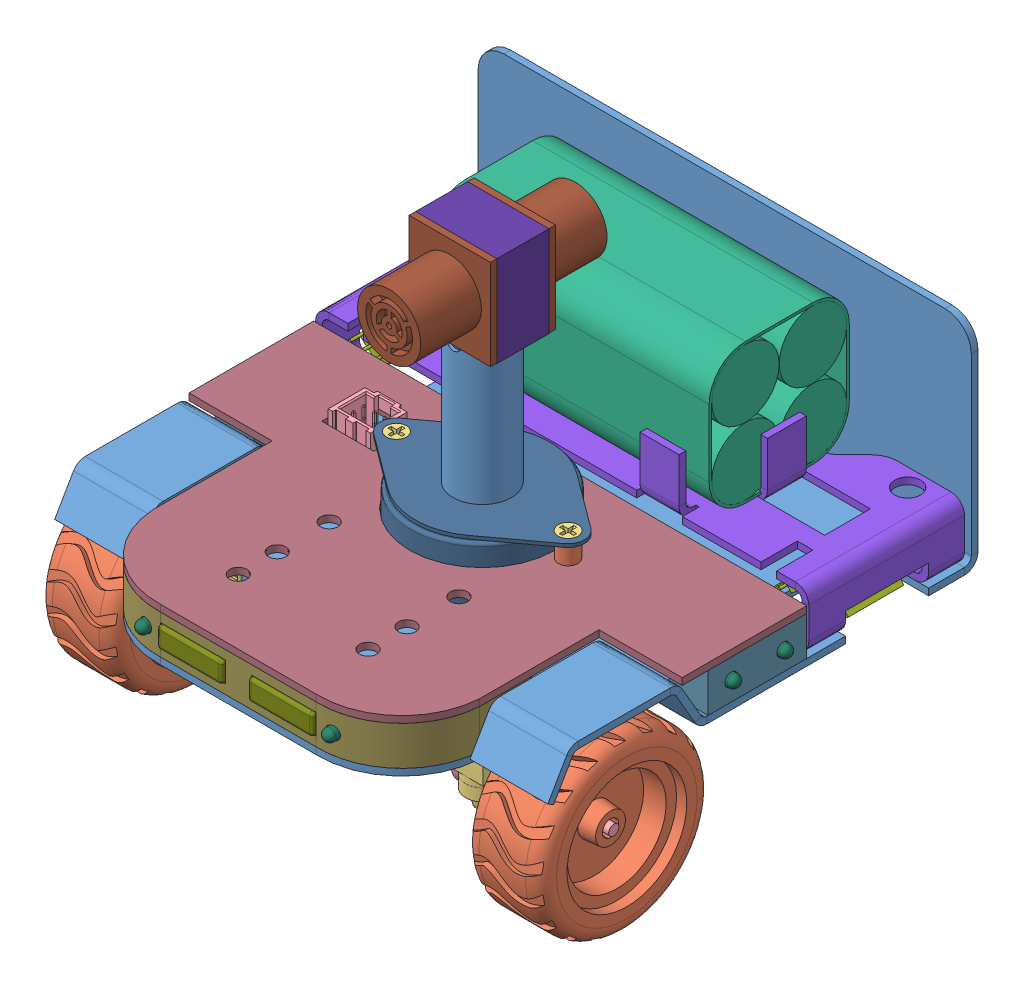
SolidWorks assembly REAR, TOP LEVEL, configuration Default. Lengths in mm.
Overall size (124.43 108.12 122.55).
41 component instances, 22 part files, 83 mates.
Components (placement in the parent):
- PLATE, REAR-1: PLATE, REAR [Default] at (-42.1312 28.0774 12.7174) size (120.65 52.45 120.66)
- WHEEL ASSEMBLY-1: WHEEL ASSEMBLY [Default-_flexible1] at (7.6153 26.9792 58.7651) x (0 0 1) z (1 0 0) size (42.46 78.6 70.03) (flexible)
  - Pololu 49x19 Wheel-1: Pololu 49x19 Wheel [Default] at (-19.8703 11.8393 2.4418) size (42.46 42.56 19)
  - Pololu Extended Micro Metal Bracket-1: Pololu Extended Micro Metal Bracket [Default] at (-19.8703 6.8393 -18.4366) size (26.6 22.49 26.04)
  - Pololu 298-1 Motor-1: Pololu 298-1 Motor [Default] at (-19.8703 11.8393 -25.1366) x (0 0 -1) z (0 1 0) size (35.87 12 10)
- WHEEL ASSEMBLY-2: WHEEL ASSEMBLY [Default-_flexible2] at (-91.8778 26.9792 19.0244) x (0 0 -1) z (-1 0 0) size (42.46 78.6 70.03) (flexible)
  - Pololu 49x19 Wheel-1: Pololu 49x19 Wheel [Default] at (-19.8703 11.8393 2.4418) size (42.46 42.56 19)
  - Pololu Extended Micro Metal Bracket-1: Pololu Extended Micro Metal Bracket [Default] at (-19.8703 6.8393 -18.4366) size (26.6 22.49 26.04)
  - Pololu 298-1 Motor-1: Pololu 298-1 Motor [Default] at (-19.8703 11.8393 -25.1366) x (0 0 -1) z (0 1 0) size (35.87 12 10)
- Socket Head Cap Screw_AI-1: Socket Head Cap Screw_AI [HX-SHCS 0.086-56x0.4375x0.4375-N] at (-77.6912 31.9128 47.8948) x (0 -1 0) z (-0.381305 0 -0.924449) size (13.3 3.56 3.56)
- Socket Head Cap Screw_AI-2: Socket Head Cap Screw_AI [HX-SHCS 0.086-56x0.4375x0.4375-N] at (-77.6912 31.9128 29.8948) x (0 -1 0) z (0 0 1) size (13.3 3.56 3.56)
- Socket Head Cap Screw_AI-3: Socket Head Cap Screw_AI [HX-SHCS 0.086-56x0.4375x0.4375-N] at (-6.5712 31.9128 29.8948) x (0 -1 0) z (0 0 1) size (13.3 3.56 3.56)
- Socket Head Cap Screw_AI-4: Socket Head Cap Screw_AI [HX-SHCS 0.086-56x0.4375x0.4375-N] at (-6.5712 31.9128 47.8948) x (0 -1 0) z (0 0 1) size (13.3 3.56 3.56)
- 4000mAh 7.4V Battery Pack-1: 4000mAh 7.4V Battery Pack [Default] at (-42.1312 61.2244 -25.7652) x (0 0 -1) z (1 0 0) size (34.29 34.29 68.58)
- SENSOR, GP2Y0D810-1: SENSOR, GP2Y0D810 [Default] at (9.9271 36.6454 -23.9555) x (0 0 -1) z (0.766044 0.642788 0) size (28.32 10.54 8.89)
- SENSOR, GP2Y0D810-2: SENSOR, GP2Y0D810 [Default] at (-94.1896 36.6454 -23.9555) x (0 0 -1) z (0.766044 -0.642788 0) size (28.32 10.54 8.89)
- Battery Support-1: Battery Support [Default] at (-42.1312 29.7284 -26.0192) size (120.65 27.05 38.1)
- Mounting Block-1: Mounting Block [Default] at (-42.1312 36.0784 -35.6712) x (-1 0 0) z (0 0 -1) size (22.23 12.7 25.4)
- PF35T-48-1: PF35T-48 [Default] at (-42.1312 31.7284 12.5888) size (50 29.2 35)
- MaxSonar EZ1-1: MaxSonar EZ1 [Default] at (-42.1452 90.9244 18.9388) x (0.999998 0 0.0022) z (-0.0022 0 0.999998) size (19.94 22.1 16.38)
- MaxSonar EZ1-2: MaxSonar EZ1 [Default] at (-42.1173 90.9244 6.2388) x (-0.999998 0 -0.0022) z (0.0022 0 -0.999998) size (19.94 22.1 16.38)
- BUMPER, REAR-1: BUMPER, REAR [Default] at (-42.1312 29.7284 53.2288) x (-1 0 0) z (0 0 -1) size (80.01 9.53 31.76)
- PLATE, REAR COVER-1: PLATE, REAR COVER [Default] at (-42.1312 39.2534 72.2788) size (120.65 1.65 78.75)
- MOUNTING BLOCK, COLOR SENSOR-1: MOUNTING BLOCK, COLOR SENSOR [Default] at (-97.6937 29.7284 5.6038) size (9.53 9.53 24.13)
- MOUNTING BLOCK, COLOR SENSOR-2: MOUNTING BLOCK, COLOR SENSOR [Default] at (13.4313 29.7284 5.6038) size (9.53 9.53 24.13)
- SENSOR, COLOR LED-1: SENSOR, COLOR LED [Default] at (-27.6486 42.7147 33.8533) x (0 0 -1) z (-0.713616 0.700538 0) size (5.83 3.66 3.66)
- SENSOR, COLOR LED-2: SENSOR, COLOR LED [Default] at (-64.9673 22.7516 33.8533) x (0 0 -1) z (0.002041 -0.999998 0) size (5.83 3.66 3.66)
- COPPER CONTACT-1: COPPER CONTACT [Default] at (-53.2437 34.4909 66.8178) size (15.88 5.08 6.35)
- COPPER CONTACT-2: COPPER CONTACT [Default] at (-31.0187 34.4909 66.8178) size (15.88 5.08 6.35)
- MOUNTING BLOCK, SONAR-1: MOUNTING BLOCK, SONAR [Default] at (-42.1173 90.8609 6.2388) x (0.999998 0 0.0022) z (-0.0022 0 0.999998) size (19.94 22.23 12.7)
- SHAFT, SONAR MOUNT-1: SHAFT, SONAR MOUNT [Default] at (-42.1312 52.5784 12.5888) x (-0.538443 0 0.842662) z (-0.842662 0 -0.538443) size (4.76 39.88 4.76)
- SHAFT, SONAR SUPPORT-1: SHAFT, SONAR SUPPORT [Default] at (-42.1312 46.7284 12.5888) size (14.22 33.25 14.22)
- SHAFT, STEPPER SUPPORT-1: SHAFT, STEPPER SUPPORT [Default] at (-63.1312 29.6724 12.5888) size (4.76 16.26 4.76)
- SHAFT, STEPPER SUPPORT-2: SHAFT, STEPPER SUPPORT [Default] at (-21.1312 29.6724 12.5888) x (0.987866 0 -0.155311) z (0.155311 0 0.987866) size (4.76 16.26 4.76)
- Flat Head 100 Screw_AI-2: Flat Head 100 Screw_AI [CR-FHM1 0.112-40x0.25x0.25-N] at (-63.1312 46.7284 12.5888) x (0 -1 0) z (0 0 1) size (6.35 4.85 4.85)
- Flat Head 100 Screw_AI-3: Flat Head 100 Screw_AI [CR-FHM1 0.112-40x0.25x0.25-N] at (-21.1312 46.7284 12.5888) x (0 -1 0) z (0 0 1) size (6.35 4.85 4.85)
- CONNECTOR, MOLEX 6 PIN-1: CONNECTOR, MOLEX 6 PIN [Default] at (-73.7219 38.6294 8.6439) size (10.34 13.8 9.75)
- SENSOR, COLOR LED-3: SENSOR, COLOR LED [Default] at (-64.0196 42.7147 3.5765) x (1 0 0) z (0 0.700538 -0.713616) size (5.83 3.66 3.66)
- SENSOR, COLOR LED-4: SENSOR, COLOR LED [Default] at (-64.0196 42.7147 -9.1235) x (1 0 0) z (0 0.700538 -0.713616) size (5.83 3.66 3.66)
- SENSOR, COLOR LED-5: SENSOR, COLOR LED [Default] at (-20.2429 42.7147 20.3311) x (-1 0 0) z (0 0.700538 0.713616) size (5.83 3.66 3.66)
- SENSOR, COLOR LED-6: SENSOR, COLOR LED [Default] at (-20.2429 42.7147 7.6311) x (-1 0 0) z (0 0.700538 0.713616) size (5.83 3.66 3.66)
Mates (geometry in assembly coordinates):
- Coincident1: coincident aligned: plane of WHEEL ASSEMBLY-1/Pololu Extended Micro Metal Bracket-1 through (6.4788 20.1399 25.5948) normal (0 1 0); plane of WHEEL ASSEMBLY-2/Pololu Extended Micro Metal Bracket-1 through (-90.7412 20.1399 52.1948) normal (0 1 0)
- Coincident2: coincident anti-aligned: plane of PLATE, REAR-1 through (-82.1362 28.0774 18.9388) normal (0 -1 0); plane of WHEEL ASSEMBLY-2/Pololu Extended Micro Metal Bracket-1 through (-66.7356 28.0774 52.1948) normal (0 1 0)
- Coincident3: coincident aligned: plane of Socket Head Cap Screw_AI-1 through (-77.6912 31.9128 47.8948) normal (0 1 0); plane of Socket Head Cap Screw_AI-2 through (-77.6912 31.9128 29.8948) normal (0 1 0)
- Coincident4: coincident aligned: plane of Socket Head Cap Screw_AI-3 through (-6.5712 31.9128 29.8948) normal (0 1 0); plane of Socket Head Cap Screw_AI-4 through (-6.5712 31.9128 47.8948) normal (0 1 0)
- Coincident5: coincident aligned: plane of Socket Head Cap Screw_AI-2 through (-77.6912 31.9128 29.8948) normal (0 1 0); plane of Socket Head Cap Screw_AI-3 through (-6.5712 31.9128 29.8948) normal (0 1 0)
- Coincident6: coincident anti-aligned: plane of PLATE, REAR-1 through (-82.1362 29.7284 18.9388) normal (0 1 0); plane of Socket Head Cap Screw_AI-3 through (-4.7932 29.7284 29.8948) normal (0 -1 0)
- Concentric6: concentric aligned: cylinder of PLATE, REAR-1; cylinder of Socket Head Cap Screw_AI-2
- Concentric7: concentric aligned: cylinder of PLATE, REAR-1; cylinder of Socket Head Cap Screw_AI-1
- Concentric8: concentric aligned: cylinder of PLATE, REAR-1; cylinder of Socket Head Cap Screw_AI-3
- Concentric9: concentric aligned: cylinder of PLATE, REAR-1; cylinder of Socket Head Cap Screw_AI-4
- Concentric40: concentric aligned: cylinder of WHEEL ASSEMBLY-2/Pololu Extended Micro Metal Bracket-1; cylinder of Socket Head Cap Screw_AI-2
- Concentric41: concentric aligned: cylinder of WHEEL ASSEMBLY-2/Pololu Extended Micro Metal Bracket-1; cylinder of Socket Head Cap Screw_AI-1
- Concentric42: concentric aligned: cylinder of WHEEL ASSEMBLY-1/Pololu Extended Micro Metal Bracket-1; cylinder of Socket Head Cap Screw_AI-3
- Concentric43: concentric aligned: cylinder of WHEEL ASSEMBLY-1/Pololu Extended Micro Metal Bracket-1; cylinder of Socket Head Cap Screw_AI-4
- Coincident91: coincident aligned: plane of PLATE, REAR-1 through (-42.1312 28.0774 12.7174) normal (1 0 0); plane of 4000mAh 7.4V Battery Pack-1 through (-42.1312 61.2244 -25.7652) normal (1 0 0)
- Coincident92: coincident anti-aligned: plane of PLATE, REAR-1 through (-85.9462 29.7284 -31.0357) normal (0.642788 0.766044 0); plane of SENSOR, GP2Y0D810-2 through (-97.5946 39.5026 -35.8427) normal (-0.642788 -0.766044 0)
- Concentric44: concentric aligned: cylinder of PLATE, REAR-1; cylinder of SENSOR, GP2Y0D810-2
- Parallel1: parallel anti-aligned: plane of PLATE, REAR-1 through (-97.7091 37.4434 -31.0357) normal (0 0 1); plane of SENSOR, GP2Y0D810-2 through (-89.7641 35.0043 -35.8427) normal (0 0 -1)
- Coincident93: coincident anti-aligned: plane of PLATE, REAR-1 through (1.6838 29.7284 -31.0357) normal (-0.642788 0.766044 0); plane of SENSOR, GP2Y0D810-1 through (6.522 33.7882 -35.8427) normal (0.642788 -0.766044 0)
- Concentric45: concentric aligned: cylinder of PLATE, REAR-1; cylinder of SENSOR, GP2Y0D810-1
- Parallel2: parallel aligned: plane of SENSOR, GP2Y0D810-1 through (12.3118 40.7187 -14.3797) normal (0.766044 0.642788 0); plane of PLATE, REAR-1 through (13.4467 37.4434 -35.7982) normal (0.766044 0.642788 0)
- Coincident97: coincident anti-aligned: plane of PLATE, REAR-1 through (-82.1362 29.7284 18.9388) normal (0 1 0); plane of Battery Support-1 through (18.1938 29.7284 -6.9692) normal (0 -1 0)
- Coincident98: coincident aligned: plane of PLATE, REAR-1 through (-42.1312 28.0774 12.7174) normal (1 0 0); plane of Battery Support-1 through (-42.1312 29.7284 -26.0192) normal (1 0 0)
- Coincident100: coincident aligned: plane of PLATE, REAR-1 through (-102.4562 28.0774 -36.3062) normal (0 0 1); plane of Battery Support-1 through (-89.7562 33.0304 -36.3062) normal (0 0 1)
- Coincident101: coincident anti-aligned: plane of 4000mAh 7.4V Battery Pack-1 through (-76.4212 69.4794 -8.6202) normal (0 0 1); plane of Battery Support-1 through (-23.0812 44.0794 -8.6202) normal (0 0 -1)
- Coincident102: coincident anti-aligned: plane of 4000mAh 7.4V Battery Pack-1 through (-76.4212 44.0794 -17.5102) normal (0 -1 0); plane of Battery Support-1 through (-102.4562 44.0794 -6.9692) normal (0 1 0)
- Coincident103: coincident anti-aligned: plane of PLATE, REAR-1 through (-82.1362 29.7284 18.9388) normal (0 1 0); plane of Mounting Block-1 through (-31.0187 29.7284 -48.3712) normal (0 -1 0)
- Concentric46: concentric aligned: cylinder of PLATE, REAR-1; cylinder of Mounting Block-1
- Concentric54: concentric aligned: cylinder of PLATE, REAR-1; cylinder of Mounting Block-1
- Coincident104: coincident anti-aligned: plane of PLATE, REAR-1 through (-82.1362 29.7284 18.9388) normal (0 1 0); plane of PF35T-48-1 through (-42.1312 29.7284 12.5888) normal (0 -1 0)
- Coincident105: coincident anti-aligned: plane of PLATE, REAR-1 through (-82.1362 29.7284 18.9388) normal (0 1 0); plane of BUMPER, REAR-1 through (-22.4072 29.7284 51.97) normal (0 -1 0)
- Coincident107: coincident aligned: plane of PLATE, REAR-1 through (-61.1812 28.0774 72.2788) normal (0 0 1); plane of BUMPER, REAR-1 through (-23.0812 39.2534 72.2788) normal (0 0 1)
- Concentric57: concentric anti-aligned: cylinder of PLATE, REAR-1; cylinder of BUMPER, REAR-1
- Coincident108: coincident anti-aligned: plane of BUMPER, REAR-1 through (-22.4072 39.2534 51.97) normal (0 1 0); plane of PLATE, REAR COVER-1 through (-61.8553 39.2534 51.97) normal (0 -1 0)
- Coincident109: coincident aligned: plane of PLATE, REAR-1 through (-61.1812 28.0774 72.2788) normal (0 0 1); plane of PLATE, REAR COVER-1 through (-23.0812 40.9044 72.2788) normal (0 0 1)
- Concentric58: concentric anti-aligned: cylinder of PLATE, REAR-1; cylinder of PLATE, REAR COVER-1
- Concentric59: concentric anti-aligned: cylinder of PF35T-48-1; cylinder of PLATE, REAR COVER-1
- Coincident110: coincident aligned: plane of MOUNTING BLOCK, COLOR SENSOR-1 through (-92.9312 39.2534 -6.4612) normal (0 1 0); plane of MOUNTING BLOCK, COLOR SENSOR-2 through (18.1938 39.2534 -6.4612) normal (0 1 0)
- Coincident111: coincident anti-aligned: plane of PLATE, REAR-1 through (-82.1362 29.7284 18.9388) normal (0 1 0); plane of MOUNTING BLOCK, COLOR SENSOR-1 through (-92.9312 29.7284 -6.4612) normal (0 -1 0)
- Coincident112: coincident aligned: plane of MOUNTING BLOCK, COLOR SENSOR-1 through (-102.4562 39.2534 -6.4612) normal (0 0 -1); plane of MOUNTING BLOCK, COLOR SENSOR-2 through (8.6688 39.2534 -6.4612) normal (0 0 -1)
- Coincident113: coincident: line of PLATE, REAR-1; plane of MOUNTING BLOCK, COLOR SENSOR-1 through (-102.4562 39.2534 17.6688) normal (-1 0 0)
- Coincident114: coincident aligned: plane of PLATE, REAR-1 through (18.1938 29.7284 18.9388) normal (1 0 0); plane of MOUNTING BLOCK, COLOR SENSOR-2 through (18.1938 39.2534 17.6688) normal (1 0 0)
- Coincident115: coincident aligned: plane of PLATE, REAR COVER-1 through (-102.4562 40.9044 -6.4612) normal (0 0 -1); plane of MOUNTING BLOCK, COLOR SENSOR-2 through (8.6688 39.2534 -6.4612) normal (0 0 -1)
- Concentric60: concentric anti-aligned: cylinder of PF35T-48-1; cylinder of PLATE, REAR COVER-1
- Distance1: distance = 12.7 mm anti-aligned: plane of MaxSonar EZ1-1 through (-32.1757 101.9734 18.9607) normal (0.0022 0 -0.999998); plane of MaxSonar EZ1-2 through (-52.0867 101.9734 6.2169) normal (-0.0022 0 0.999998)
- Coincident117: coincident aligned: plane of MaxSonar EZ1-1 through (-32.1792 79.8754 20.5482) normal (0.999998 0 0.0022); plane of MaxSonar EZ1-2 through (-32.1443 79.8754 4.6732) normal (0.999998 0 0.0022)
- Concentric61: concentric anti-aligned: cylinder of MaxSonar EZ1-1; cylinder of MaxSonar EZ1-2
- Coincident119: coincident aligned: plane of SENSOR, COLOR LED-1 through (-19.2954 37.1081 68.353) normal (0 0 -1); plane of SENSOR, COLOR LED-2 through (-66.8382 32.6364 68.353) normal (0 0 -1)
- Concentric62: concentric aligned: cylinder of BUMPER, REAR-1; cylinder of SENSOR, COLOR LED-1
- Concentric63: concentric aligned: cylinder of BUMPER, REAR-1; cylinder of SENSOR, COLOR LED-2
- Distance2: distance = 3.175 mm aligned: plane of SENSOR, COLOR LED-1 through (-16.654 34.5151 69.115) normal (0 0 1); cylinder of BUMPER, REAR-1
- Coincident120: coincident aligned: plane of COPPER CONTACT-1 through (-45.3062 37.0309 73.1678) normal (0 0 1); plane of COPPER CONTACT-2 through (-23.0812 37.0309 73.1678) normal (0 0 1)
- Coincident121: coincident aligned: plane of COPPER CONTACT-1 through (-61.1812 37.0309 73.1678) normal (0 1 0); plane of COPPER CONTACT-2 through (-38.9562 37.0309 73.1678) normal (0 1 0)
- Coincident122: coincident anti-aligned: plane of BUMPER, REAR-1 through (-38.9562 31.9509 72.29) normal (0 1 0); plane of COPPER CONTACT-2 through (-38.9562 31.9509 73.1678) normal (0 -1 0)
- Coincident123: coincident anti-aligned: plane of BUMPER, REAR-1 through (-23.0812 31.9509 72.29) normal (-1 0 0); plane of COPPER CONTACT-2 through (-23.0812 31.9509 73.1678) normal (1 0 0)
- Coincident124: coincident anti-aligned: plane of BUMPER, REAR-1 through (-61.1812 31.9509 72.29) normal (1 0 0); plane of COPPER CONTACT-1 through (-61.1812 31.9509 73.1678) normal (-1 0 0)
- Distance3: distance = 0.889 mm aligned: plane of COPPER CONTACT-2 through (-23.0812 37.0309 73.1678) normal (0 0 1); plane of BUMPER, REAR-1 through (-23.0812 39.2534 72.2788) normal (0 0 1)
- Coincident125: coincident anti-aligned: plane of MaxSonar EZ1-1 through (-32.1757 101.9734 18.9607) normal (0.0022 0 -0.999998); plane of MOUNTING BLOCK, SONAR-1 through (-32.1757 101.9734 18.9607) normal (-0.0022 0 0.999998)
- Coincident126: coincident aligned: plane of MaxSonar EZ1-1 through (-32.1792 79.8754 20.5482) normal (0.999998 0 0.0022); plane of MOUNTING BLOCK, SONAR-1 through (-32.1757 79.7484 18.9607) normal (0.999998 0 0.0022)
- Coincident127: coincident aligned: plane of MaxSonar EZ1-2 through (-32.1443 101.9734 4.6732) normal (0 1 0); plane of MOUNTING BLOCK, SONAR-1 through (-52.1147 101.9734 18.9168) normal (0 1 0)
- Concentric64: concentric aligned: cylinder of PF35T-48-1; cylinder of MOUNTING BLOCK, SONAR-1
- Distance4: distance = 33.02 mm anti-aligned: plane of PF35T-48-1 through (-63.1312 46.7284 12.5888) normal (0 1 0); plane of MOUNTING BLOCK, SONAR-1 through (-52.1147 79.7484 18.9168) normal (0 -1 0)
- Coincident129: coincident anti-aligned: plane of PF35T-48-1 through (-42.1312 58.9284 12.5888) normal (0 1 0); plane of SHAFT, SONAR MOUNT-1 through (-42.1312 58.9284 12.5888) normal (0 -1 0)
- Concentric65: concentric aligned: cylinder of PF35T-48-1; cylinder of SHAFT, SONAR MOUNT-1
- Concentric66: concentric aligned: cylinder of SHAFT, SONAR MOUNT-1; cylinder of SHAFT, SONAR SUPPORT-1
- Coincident130: coincident anti-aligned: plane of PF35T-48-1 through (-63.1312 46.7284 12.5888) normal (0 1 0); plane of SHAFT, SONAR SUPPORT-1 through (-42.1312 46.7284 12.5888) normal (0 -1 0)
- Concentric67: concentric anti-aligned: cylinder of PLATE, REAR COVER-1; cylinder of SHAFT, STEPPER SUPPORT-1
- Concentric68: concentric anti-aligned: cylinder of PLATE, REAR COVER-1; cylinder of SHAFT, STEPPER SUPPORT-2
- Coincident131: coincident anti-aligned: plane of PF35T-48-1 through (-63.1312 45.9284 12.5888) normal (0 -1 0); plane of SHAFT, STEPPER SUPPORT-1 through (-63.1312 45.9284 12.5888) normal (0 1 0)
- Coincident132: coincident anti-aligned: plane of PF35T-48-1 through (-63.1312 45.9284 12.5888) normal (0 -1 0); plane of SHAFT, STEPPER SUPPORT-2 through (-21.1312 45.9284 12.5888) normal (0 1 0)
- Coincident133: coincident aligned: plane of Flat Head 100 Screw_AI-2 through (-61.7088 40.3784 12.5888) normal (0 -1 0); plane of Flat Head 100 Screw_AI-3 through (-19.7088 40.3784 12.5888) normal (0 -1 0)
- Concentric69: concentric anti-aligned: cylinder of SHAFT, STEPPER SUPPORT-2; cylinder of Flat Head 100 Screw_AI-3
- Concentric70: concentric anti-aligned: cylinder of SHAFT, STEPPER SUPPORT-1; cylinder of Flat Head 100 Screw_AI-2
- Coincident134: coincident aligned: plane of PF35T-48-1 through (-63.1312 46.7284 12.5888) normal (0 1 0); plane of Flat Head 100 Screw_AI-2 through (-63.1312 46.7284 12.5888) normal (0 1 0)
- Coincident135: coincident aligned: plane of SENSOR, COLOR LED-3 through (-98.5192 37.1081 11.9296) normal (1 0 0); plane of SENSOR, COLOR LED-4 through (-98.5192 37.1081 -0.7704) normal (1 0 0)
- Coincident136: coincident aligned: plane of SENSOR, COLOR LED-5 through (14.2568 37.1081 11.978) normal (-1 0 0); plane of SENSOR, COLOR LED-6 through (14.2568 37.1081 -0.722) normal (-1 0 0)
- Concentric71: concentric anti-aligned: cylinder of MOUNTING BLOCK, COLOR SENSOR-2; cylinder of SENSOR, COLOR LED-6
- Concentric72: concentric anti-aligned: cylinder of MOUNTING BLOCK, COLOR SENSOR-2; cylinder of SENSOR, COLOR LED-5
- Distance5: distance = 3.175 mm aligned: plane of SENSOR, COLOR LED-5 through (15.0188 34.5151 9.3365) normal (1 0 0); plane of MOUNTING BLOCK, COLOR SENSOR-2 through (18.1938 39.2534 17.6688) normal (1 0 0)
- Concentric73: concentric aligned: cylinder of SENSOR, COLOR LED-4; cylinder of MOUNTING BLOCK, COLOR SENSOR-1
- Concentric74: concentric aligned: cylinder of MOUNTING BLOCK, COLOR SENSOR-1; cylinder of SENSOR, COLOR LED-3
- Distance6: distance = 3.175 mm aligned: plane of SENSOR, COLOR LED-4 through (-99.2812 34.5151 1.871) normal (-1 0 0); plane of MOUNTING BLOCK, COLOR SENSOR-1 through (-102.4562 39.2534 17.6688) normal (-1 0 0)
- Distance7: distance = 3.175 mm aligned: plane of CONNECTOR, MOLEX 6 PIN-1 through (-68.3451 44.0794 3.5739) normal (0 1 0); plane of PLATE, REAR COVER-1 through (-61.8553 40.9044 51.97) normal (0 1 0)
